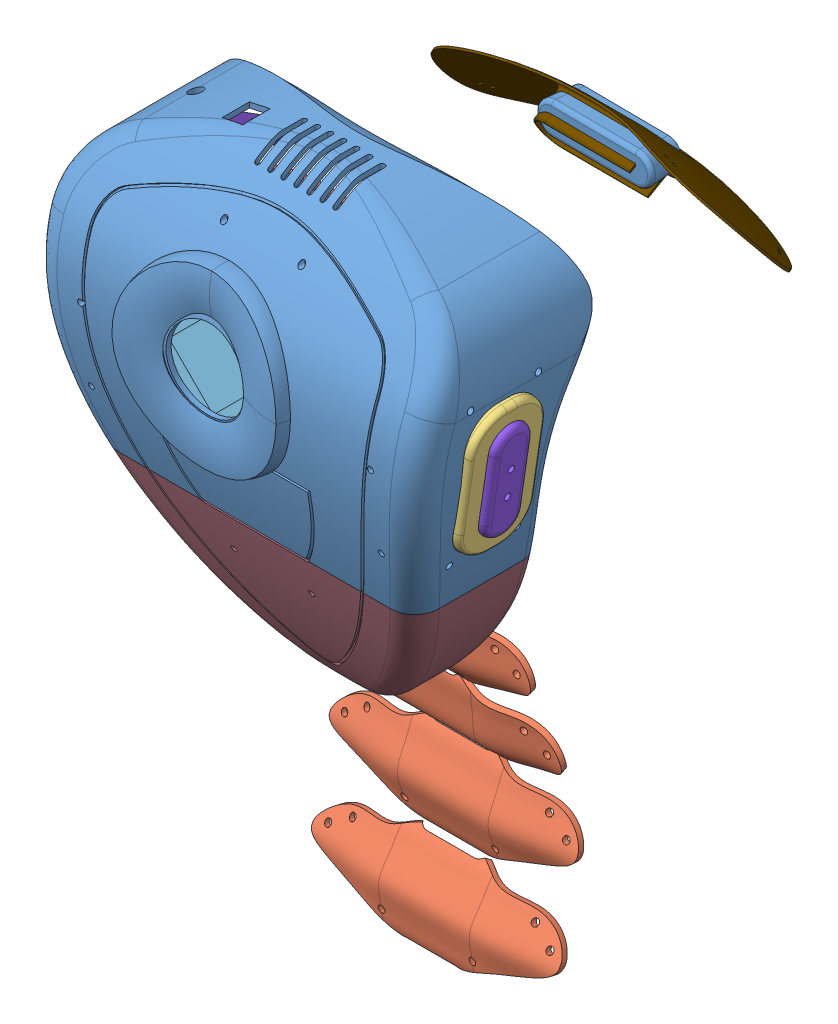
SolidWorks assembly Ensamble Mochila, configuration Default. Lengths in mm.
Overall size (331.65 592.36 403.8).
28 component instances, 20 part files, 44 mates.
Components (placement in the parent):
- backpack 2g bottom-1: backpack 2g bottom [Default] at (119.4145 250.7971 218.3899) size (331.65 355.76 156.42)
- Vertebra-1: Vertebra [Default] at (118.8196 71.875 196.4276) x (1 0 0) z (0 -0.948324 -0.317305) size (198 22.76 69.24)
- Part2-1: Part2 [Default] at (-30.5346 255.3553 293.3899) x (0.14708 -0.989125 0) z (0 0 1) size (104.05 10.05 58.05)
- Part2-2: Part2 [Default] at (269.3635 255.3553 293.3899) x (0.147081 0.989124 0) z (0 0 1) size (104.05 10.05 58.05)
- Jetson H-1: Jetson H [Default] at (-25.9313 294.8879 198.9465) x (0.707107 0.707107 0) z (0.707107 -0.707107 0) size (180 45.5 180)
  - Base-1: Base [Default] at (67.0689 90.6709 139.4266) size (180 3 180)
  - Board-1: Board [Default] at (67.0689 104.6709 139.4266) size (170 31.5 170)
  - Separador-1: Separador [Default] at (-7.9311 93.6709 214.4266) x (0.99477 0 -0.102141) z (0.102141 0 0.99477) size (6 11 6)
  - Separador-2: Separador [Default] at (142.0689 93.6709 64.4266) size (6 11 6)
  - Separador-3: Separador [Default] at (142.0689 93.6709 214.4266) size (6 11 6)
  - Separador-4: Separador [Default] at (-7.9311 93.6709 64.4266) size (6 11 6)
- Vertebra-2: Vertebra [Default] at (118.376 8.3161 174.5883) x (1 0 0) z (0 -0.913545 -0.406737) size (198 22.76 69.24)
- Vertebra-3: Vertebra [Default] at (118.6698 -138.0838 164.6524) x (1 0 0) z (0 -0.97237 0.233445) size (198 22.76 69.24)
- Vertebra-4: Vertebra [Default] at (118.6834 -66.4172 153.1876) x (1 0 0) z (0 -0.998135 0.061049) size (198 22.76 69.24)
- Pieza soporte bocina izquierda-1: Pieza soporte bocina izquierda [Default] at (249.7444 259.3959 292.8923) x (0.989124 -0.147081 0) z (0 0 1) size (30.45 130 93.17)
- Seguro bocina izquierda-1: Seguro bocina izquierda [Default] at (260.7409 231.3626 293.3899) x (0 0 -1) z (-0.147081 -0.989124 0) size (30 10.46 80)
- jetson holder ---1: jetson holder -- [Default] at (120.0816 243.7182 283.6173) x (-0.707107 0.707107 0) z (0.707107 0.707107 0) size (66.79 36.44 66.79)
- jetson holder ++-1: jetson holder ++ [Default] at (120.0846 243.7282 283.6173) x (0.707107 -0.707107 0) z (-0.707107 -0.707107 0) size (66.79 46.69 66.79)
- jetson holder -+-1: jetson holder -+ [Default] at (120.0781 243.7248 283.6173) x (0.707107 0.707107 0) z (0.707107 -0.707107 0) size (66.79 69.99 66.79)
- jetson holder +--1: jetson holder +- [Default] at (120.0881 243.7217 283.6173) x (-0.707107 -0.707107 0) z (-0.707107 0.707107 0) size (49.73 64.72 58.31)
- backpack 2g-2: backpack 2g [Default] at (119.4145 250.7971 218.3899) size (250.08 344.21 137.51)
- Pieza soporte bocina derecha-1: Pieza soporte bocina derecha [Default] at (8.867 262.3374 292.8923) x (0.989125 0.14708 0) z (0 0 1) size (17.29 130.75 82.59)
- Seguro bocina der-1: Seguro bocina der [Default] at (-68.831 274.9356 293.3899) x (0 0 1) z (-0.14708 0.989125 0) size (30 10.46 80)
- Union left-1: Union left [Default] at (232.1995 167.8342 278.3854) x (0.008119 -0.003198 -0.999962) z (0.930382 -0.366487 0.008727) size (60 40 6.53)
- Sensores-1: Sensores [Default] at (34.9607 359.3668 269.7709) x (-0.936644 -0.350185 -0.008276) z (0.006782 0.005492 -0.999962) size (110 12.3 30)
- Pecho-1: Pecho [Default] at (116.361 294.6343 51.4593) x (-0.999962 -0.006171 -0.006171) z (0.008727 -0.70708 -0.70708) size (284.4 58.67 170.86)
- Realsense-1: Realsense [Default] at (117.2497 289.9091 71.9103) x (-0.999962 0 -0.008727) z (0.008727 0 -0.999962) size (89.45 24.73 25)
- Broche-1: Broche [Default] at (120.0846 243.7282 283.6173) x (0.965926 -0.258819 0) z (0.258819 0.965926 0) size (250 4 250)
Mates (geometry in assembly coordinates):
- Coincident1: coincident: point of backpack 2g bottom-1; unknown of Part2-2
- Coincident2: coincident: curve of backpack 2g bottom-1; unknown of Part2-2
- Coincident3: coincident anti-aligned: plane of backpack 2g bottom-1 through (-50.2025 228.7971 264.3899) normal (0 0 1); plane of Part2-2 through (263.4435 283.5325 264.3899) normal (0 0 -1)
- Coincident4: coincident: unknown of backpack 2g bottom-1; unknown of Part2-1
- Coincident5: coincident: edge_curve of backpack 2g bottom-1; unknown of Part2-1
- Coincident6: coincident anti-aligned: plane of backpack 2g bottom-1 through (-50.2025 228.7971 264.3899) normal (0 0 1); plane of Part2-1 through (-16.6722 230.1198 264.3899) normal (0 0 -1)
- Concentric1: concentric aligned: cylinder of backpack 2g bottom-1 through (331.3037 303.8839 266.8923) axis (-0.989124 0.147081 0) radius 2.5; cylinder of Pieza soporte bocina izquierda-1 through (272.8178 312.5806 266.8923) axis (-0.989124 0.147081 0) radius 2.5
- Concentric2: concentric aligned: cylinder of backpack 2g bottom-1 through (331.3037 303.8839 318.8923) axis (-0.989124 0.147081 0) radius 2.5; cylinder of Pieza soporte bocina izquierda-1 through (272.8178 312.5806 318.8923) axis (-0.989124 0.147081 0) radius 2.5
- Coincident7: coincident anti-aligned: plane of Part2-2 through (255.5011 230.1198 289.3899) normal (-0.989124 0.147081 0); plane of Pieza soporte bocina izquierda-1 through (255.5011 230.1198 289.3899) normal (0.989124 -0.147081 0)
- Concentric3: concentric aligned: cylinder of Pieza soporte bocina izquierda-1 through (245.6146 268.9967 293.3899) axis (0.989124 -0.147081 0) radius 2.5; cylinder of Seguro bocina izquierda-1 through (265.4344 266.0495 293.3899) axis (0.989124 -0.147081 0) radius 2.5
- Concentric4: concentric aligned: cylinder of Pieza soporte bocina izquierda-1 through (242.673 249.2142 293.3899) axis (0.989124 -0.147081 0) radius 2.5; cylinder of Seguro bocina izquierda-1 through (262.4928 246.267 293.3899) axis (0.989124 -0.147081 0) radius 2.5
- Coincident8: coincident anti-aligned: plane of Pieza soporte bocina izquierda-1 through (264.5813 257.1896 292.8923) normal (0.989124 -0.147081 0); plane of Seguro bocina izquierda-1 through (260.7409 231.3626 293.3899) normal (-0.989124 0.147081 0)
- Concentric5: concentric anti-aligned: cylinder of Jetson H-1/Base-1 through (110.0816 132.6368 292.6173) axis (0 0 -1) radius 2.5; cylinder of jetson holder ---1 through (110.0816 132.6368 283.6163) axis (0 0 1) radius 2.5
- Parallel1: parallel anti-aligned: cylinder of Jetson H-1/Base-1 through (130.0816 132.6368 292.6173) axis (0 0 -1) radius 2.5; cylinder of jetson holder ---1 through (130.0816 132.6368 283.6163) axis (0 0 1) radius 2.5
- Coincident9: coincident anti-aligned: plane of Jetson H-1/Base-1 through (120.0831 243.7232 289.6173) normal (0 0 -1); plane of jetson holder ---1 through (120.0816 243.7182 289.6173) normal (0 0 1)
- Coincident10: coincident aligned: circle of Jetson H-1/Base-1; cylinder of jetson holder ++-1 through (130.0846 354.8097 283.6163) axis (0 0 1) radius 2.5
- Parallel2: parallel anti-aligned: cylinder of Jetson H-1/Base-1 through (110.0846 354.8097 292.6173) axis (0 0 -1) radius 2.5; cylinder of jetson holder ++-1 through (110.0846 354.8097 283.6163) axis (0 0 1) radius 2.5
- Coincident11: coincident anti-aligned: plane of Jetson H-1/Base-1 through (120.0831 243.7232 289.6173) normal (0 0 -1); plane of jetson holder ++-1 through (120.0846 243.7282 289.6173) normal (0 0 1)
- Concentric8: concentric anti-aligned: cylinder of Jetson H-1/Base-1 through (8.9966 253.7248 292.6173) axis (0 0 -1) radius 2.5; cylinder of jetson holder -+-1 through (8.9966 253.7248 283.6163) axis (0 0 1) radius 2.5
- Parallel3: parallel anti-aligned: cylinder of Jetson H-1/Base-1 through (8.9966 233.7248 292.6173) axis (0 0 -1) radius 2.5; cylinder of jetson holder -+-1 through (8.9966 233.7248 283.6163) axis (0 0 1) radius 2.5
- Coincident12: coincident anti-aligned: plane of Jetson H-1/Base-1 through (120.0831 243.7232 289.6173) normal (0 0 -1); plane of jetson holder -+-1 through (120.0781 243.7248 289.6173) normal (0 0 1)
- Concentric10: concentric anti-aligned: cylinder of Jetson H-1/Base-1 through (231.1696 233.7217 292.6173) axis (0 0 -1) radius 2.5; cylinder of jetson holder +--1 through (231.1696 233.7217 283.6163) axis (0 0 1) radius 2.5
- Parallel4: parallel anti-aligned: cylinder of Jetson H-1/Base-1 through (231.1696 253.7217 292.6173) axis (0 0 -1) radius 2.5; cylinder of jetson holder +--1 through (231.1696 253.7217 283.6163) axis (0 0 1) radius 2.5
- Coincident13: coincident anti-aligned: plane of Jetson H-1/Base-1 through (120.0831 243.7232 289.6173) normal (0 0 -1); plane of jetson holder +--1 through (120.0881 243.7217 289.6173) normal (0 0 1)
- Parallel5: parallel anti-aligned: cylinder of Jetson H-1/Base-1 through (110.0846 354.8097 292.6173) axis (0 0 -1) radius 2.5; cylinder of jetson holder ++-1 through (110.0846 354.8097 283.6163) axis (0 0 1) radius 2.5
- Parallel6: parallel anti-aligned: cylinder of Jetson H-1/Base-1 through (110.0846 354.8097 292.6173) axis (0 0 -1) radius 2.5; cylinder of jetson holder ++-1 through (110.0846 354.8097 283.6163) axis (0 0 1) radius 2.5
- Concentric15: concentric anti-aligned: cylinder of Jetson H-1/Base-1 through (110.0846 354.8097 292.6173) axis (0 0 -1) radius 2.5; cylinder of jetson holder ++-1 through (110.0846 354.8097 283.6163) axis (0 0 1) radius 2.5
- Concentric16: concentric anti-aligned: cylinder of Jetson H-1/Base-1 through (8.9966 233.7248 292.6173) axis (0 0 -1) radius 2.5; cylinder of jetson holder -+-1 through (8.9966 233.7248 283.6163) axis (0 0 1) radius 2.5
- Concentric17: concentric anti-aligned: cylinder of Jetson H-1/Base-1 through (130.0816 132.6368 292.6173) axis (0 0 -1) radius 2.5; cylinder of jetson holder ---1 through (130.0816 132.6368 283.6163) axis (0 0 1) radius 2.5
- Concentric18: concentric anti-aligned: cylinder of Jetson H-1/Base-1 through (231.1696 253.7217 292.6173) axis (0 0 -1) radius 2.5; cylinder of jetson holder +--1 through (231.1696 253.7217 283.6163) axis (0 0 1) radius 2.5
- Concentric19: concentric aligned: cylinder of backpack 2g bottom-1 through (90.3204 354.8097 376.5741) axis (0 0 -1) radius 2.25; cylinder of jetson holder ++-1 through (90.3204 354.8097 333.6173) axis (0 0 -1) radius 2.5
- Concentric20: concentric aligned: cylinder of backpack 2g bottom-1 through (149.8488 354.8097 376.5741) axis (0 0 -1) radius 2.25; cylinder of jetson holder ++-1 through (149.8488 354.8097 333.6173) axis (0 0 -1) radius 2.5
- Coincident15: coincident: unknown of backpack 2g bottom-1; unknown of backpack 2g-2
- Coincident16: coincident: unknown of backpack 2g bottom-1; unknown of backpack 2g-2
- Coincident17: coincident anti-aligned: plane of Part2-1 through (-24.6145 283.5325 289.3899) normal (0.989125 0.14708 0); plane of Pieza soporte bocina derecha-1 through (-16.6722 230.1198 289.3899) normal (-0.989125 -0.14708 0)
- Coincident18: coincident: unknown of Part2-1; unknown of Pieza soporte bocina derecha-1
- Coincident19: coincident: unknown of Part2-1; unknown of Pieza soporte bocina derecha-1
- Concentric21: concentric aligned: cylinder of Pieza soporte bocina derecha-1 through (-6.7857 268.9967 293.3899) axis (-0.989125 -0.14708 0) radius 2.5; cylinder of Seguro bocina der-1 through (-26.6055 266.0495 293.3899) axis (-0.989125 -0.14708 0) radius 2.5
- Concentric22: concentric aligned: cylinder of Pieza soporte bocina derecha-1 through (-3.8441 249.2142 293.3899) axis (-0.989125 -0.14708 0) radius 2.5; cylinder of Seguro bocina der-1 through (-23.6639 246.267 293.3899) axis (-0.989125 -0.14708 0) radius 2.5
- Coincident20: coincident anti-aligned: plane of Pieza soporte bocina derecha-1 through (-25.7524 257.1896 292.8923) normal (-0.989125 -0.14708 0); plane of Seguro bocina der-1 through (-29.266 280.8188 293.3899) normal (0.989125 0.14708 0)
- Coincident21: coincident: unknown of backpack 2g bottom-1; unknown of backpack 2g-2
- Coincident22: coincident anti-aligned: plane of jetson holder ++-1 through (120.0846 243.7282 283.6173) normal (0 0 -1); plane of Broche-1 through (120.0846 243.7282 283.6173) normal (0 0 1)
- Concentric23: concentric anti-aligned: cylinder of jetson holder ++-1 through (149.8488 354.8097 333.6173) axis (0 0 -1) radius 2.5; cylinder of Broche-1 through (149.8488 354.8097 279.6173) axis (0 0 1) radius 2.5
- Concentric24: concentric anti-aligned: cylinder of jetson holder ++-1 through (90.3204 354.8097 333.6173) axis (0 0 -1) radius 2.5; cylinder of Broche-1 through (90.3204 354.8097 279.6173) axis (0 0 1) radius 2.5
